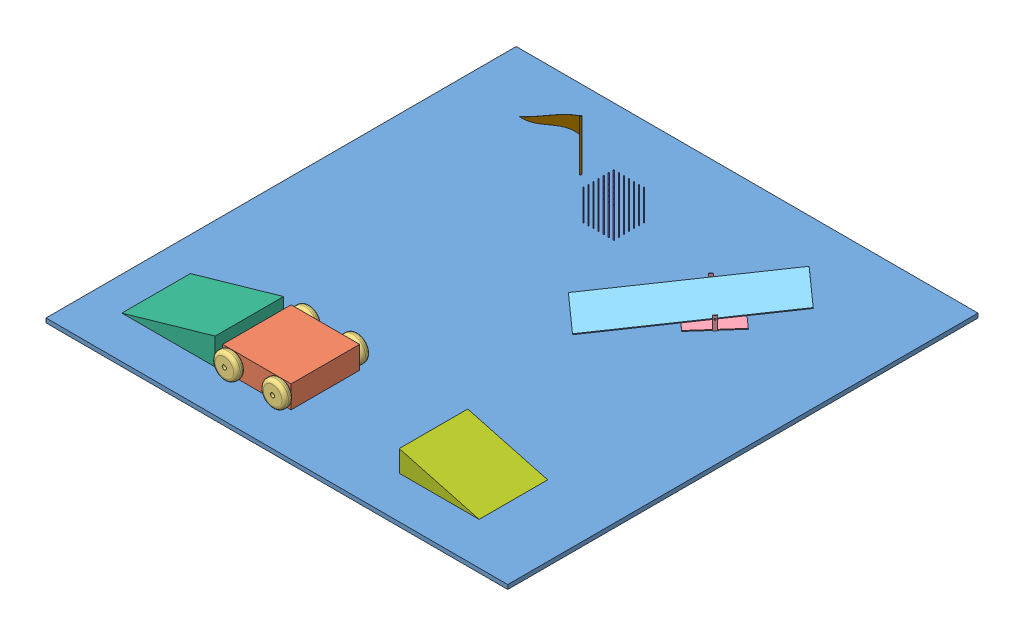
SolidWorks assembly Arena, configuration Default. Lengths in mm.
Overall size (2740 331.31 2790).
14 component instances, 9 part files, 13 mates.
Components (placement in the parent):
- Tabletop-1: Tabletop [Default] at (-1236.259 66.7354 607.018) size (2740 25.4 2790)
- YoshiRover-1: YoshiRover [Default] at (-438.2724 97.1354 1747.4655) size (478.12 206.77 506.4)
  - YoshiBase-1: YoshiBase [Default] at origin size (406.4 133.35 406.4)
  - YoshiWheel-1: YoshiWheel [Default] at (60 70 0) x (0.964205 0.265159 0) z (0 0 1) size (150 150 50)
  - YoshiWheel-2: YoshiWheel [Default] at (346.4 70 0) x (0.999908 -0.0136 0) z (0 0 1) size (150 150 50)
  - YoshiWheel-3: YoshiWheel [Default] at (60 70 -456.4) x (0.847197 -0.531279 0) z (0 0 1) size (150 150 50)
  - YoshiWheel-4: YoshiWheel [Default] at (346.4 70 -456.4) x (0.980305 -0.197488 0) z (0 0 1) size (150 150 50)
- PerfStageSeeSaw-1: PerfStageSeeSaw [Default] at (719.0572 92.1354 181.1204) x (0.66555 0 -0.746353) z (0.746353 0 0.66555) size (1012.1 100.9 310)
  - NSeeSawBase-1: NSeeSawBase [Default] at origin size (280 80 310)
  - NSeeSawPlank-1: NSeeSawPlank [Default] at (-458.4312 1.8123 0) x (0.995701 0.092623 0) z (0 0 1) size (1016 5 300)
- YoshiUpRamp-1: YoshiUpRamp [Default] at (-482.632 92.1354 1747.4655) size (553.63 158.75 406.4)
- YoshiDownRamp-1: YoshiDownRamp [Default] at (609.7705 92.1354 1747.4655) size (473.97 127 406.4)
- LedCube^Arena-1: LedCube^Arena [Default] at (-132.1375 92.1354 -87.3999) size (185 180 185) (virtual)
- Flag^Arena-1: Flag^Arena [Default] at (-388.0621 92.1354 -326.5683) x (-0.512601 0 -0.858627) z (0.858627 0 -0.512601) size (10 302.93 270.27) (virtual)
Mates (geometry in assembly coordinates):
- Coincident5: coincident anti-aligned: plane of Tabletop-1 through (-1236.259 92.1354 -792.5345) normal (0 1 0); plane of PerfStageSeeSaw-1/NSeeSawBase-1 through (719.0572 92.1354 181.1204) normal (0 -1 0)
- Parallel3: parallel anti-aligned: plane of Tabletop-1 through (-1236.259 92.1354 -792.5345) normal (0 1 0); plane of YoshiRover-1/YoshiBase-1 through (-438.2724 97.1354 1747.4655) normal (0 -1 0)
- Tangent1: tangent anti-aligned: plane of Tabletop-1 through (-1236.259 92.1354 -792.5345) normal (0 1 0); cylinder of YoshiRover-1/YoshiWheel-1 through (-378.2724 167.1354 1797.4655) axis (0 0 -1) radius 75
- Distance5: distance = 200 mm: line of Tabletop-1 through (-1236.259 92.1354 -792.5345) axis (0 0 1); line of YoshiUpRamp-1 through (-1036.259 92.1354 1341.0655) axis (0 0 1)
- Distance6: distance = 420 mm: line of Tabletop-1 through (1503.741 92.1354 1997.4655) axis (0 0 -1); line of YoshiDownRamp-1 through (1083.741 92.1354 1341.0655) axis (0 0 1)
- Distance4: distance = 250 mm aligned: plane of YoshiUpRamp-1 through (-482.632 92.1354 1747.4655) normal (0 0 1); plane of Tabletop-1 through (-1236.259 92.1354 1997.4655) normal (0 0 1)
- Coincident16: coincident aligned: plane of YoshiUpRamp-1 through (-482.632 92.1354 1747.4655) normal (0 0 1); plane of YoshiDownRamp-1 through (609.7705 92.1354 1747.4655) normal (0 0 1)
- Coincident17: coincident anti-aligned: plane of Tabletop-1 through (-1236.259 92.1354 -792.5345) normal (0 1 0); plane of YoshiUpRamp-1 through (-1036.259 92.1354 1341.0655) normal (0 -1 0)
- Coincident18: coincident anti-aligned: plane of Tabletop-1 through (-1236.259 92.1354 -792.5345) normal (0 1 0); plane of YoshiDownRamp-1 through (1083.741 92.1354 1341.0655) normal (0 -1 0)
- Coincident19: coincident aligned: plane of YoshiRover-1/YoshiBase-1 through (-438.2724 230.4854 1747.4655) normal (0 0 1); plane of YoshiUpRamp-1 through (-482.632 92.1354 1747.4655) normal (0 0 1)
- Angle1: planar angle = 0.733038 rad aligned: line of PerfStageSeeSaw-1/NSeeSawPlank-1 through (413.6401 98.9261 523.6176) axis (0.662689 0.092623 -0.743145); line of Tabletop-1 through (1503.741 92.1354 1997.4655) axis (0 0 -1)
- Coincident24: coincident anti-aligned: plane of Tabletop-1 through (-1236.259 92.1354 -792.5345) normal (0 1 0); plane of LedCube^Arena-1 through (-12.1375 92.1354 -207.3999) normal (0 -1 0)
- Coincident26: coincident aligned: plane of Tabletop-1 through (-1236.259 92.1354 -792.5345) normal (0 1 0); circle of Flag^Arena-1
